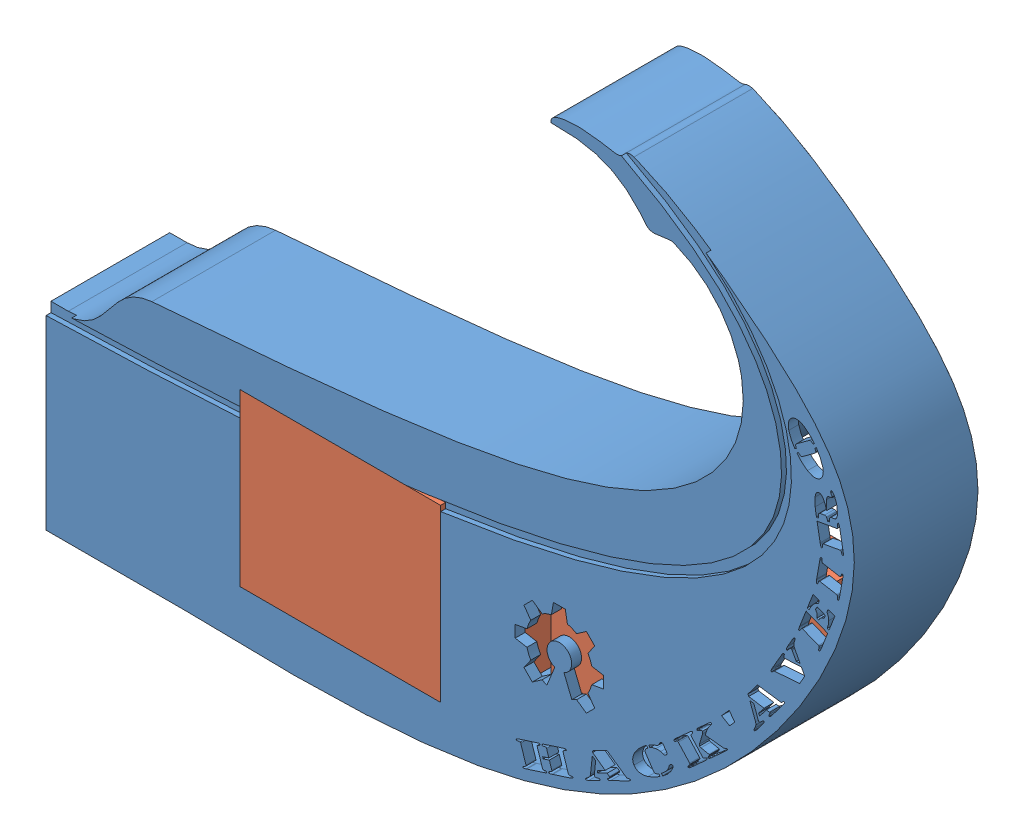
SolidWorks assembly Assem1, configuration Default. Lengths in mm.
Overall size (167.6 132.81 25).
2 component instances, 2 part files, 3 mates.
Components (placement in the parent):
- MoliceiroV4-1: MoliceiroV4 [Default] at (79.1807 68.8636 132.1955) size (167.36 132.81 25)
- ComponentsLayout-1: ComponentsLayout [Default] at (76.9307 63.6136 139.6955) x (1 0 0) z (0 -1 0) size (150.03 17.5 56.43)
Mates (geometry in assembly coordinates):
- Coincident1: coincident anti-aligned: plane of MoliceiroV4-1 through (79.1807 68.8636 157.1955) normal (1 0 0); plane of ComponentsLayout-1 through (79.1807 103.3636 157.1955) normal (-1 0 0)
- Coincident2: coincident anti-aligned: plane of MoliceiroV4-1 through (79.1807 103.3636 157.1955) normal (0 -1 0); plane of ComponentsLayout-1 through (79.1807 103.3636 157.1955) normal (0 1 0)
- Coincident3: coincident aligned: plane of MoliceiroV4-1 through (203.2526 133.6127 157.1955) normal (0 0 1); plane of ComponentsLayout-1 through (76.9307 63.6136 157.1955) normal (0 0 1)
